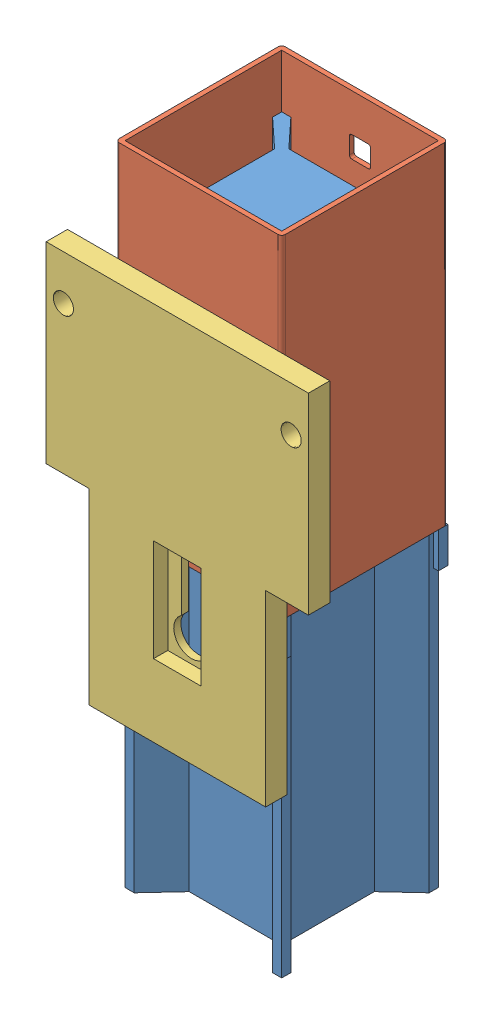
SolidWorks assembly B40-5F-, configuration Default. Lengths in mm.
Overall size (110.5 272.5 79).
3 component instances, 3 part files, 0 mates.
Components (placement in the parent):
- B00-042-KR--1: B00-042-KR- [Default] at origin size (70 250 70)
- G2284--1: G2284- [Default] at (0 77.5 0) x (0 0 -1) z (1 0 0) size (70 140 70)
- Rail_Plate--1: Rail_Plate- [Default] at (0 -55 35) size (110.5 160 9)
